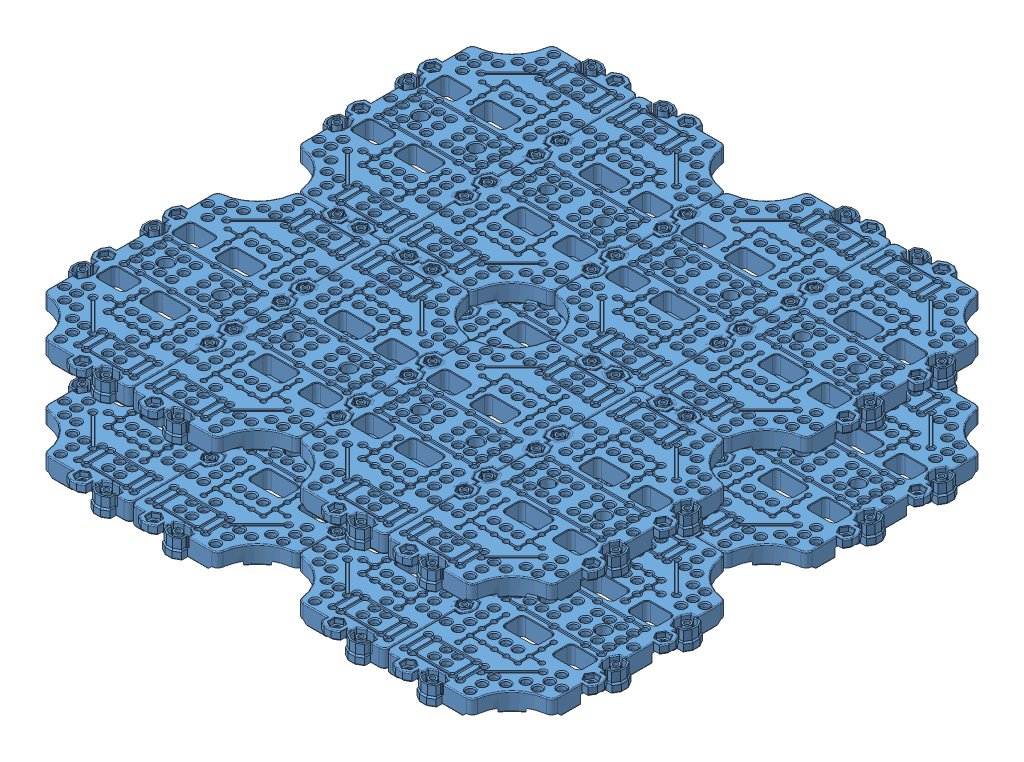
SolidWorks assembly layer, configuration 預設. Lengths in mm.
Overall size (348.29 59.85 366.75).
22 component instances, 1 part files, 0 mates.
Components (placement in the parent):
- 組合件4^layer-1: 組合件4^layer [預設] at origin size (348.29 9.85 366.75) (virtual)
  - 複製 of 組合件3^組合件4_layer-1: 複製 of 組合件3^組合件4_layer [預設] at (61.6154 0 -10.7198) size (265.55 9.85 137.55) (virtual)
    - waffle_plate - P-BP-A001_3D-1: waffle_plate - P-BP-A001_3D [Default] at (41.4794 2.9137 137.552) x (-1 0 0) z (0 0 -1) size (73.55 9.85 137.55)
    - waffle_plate - P-BP-A001_3D-2: waffle_plate - P-BP-A001_3D [Default] at (-86.5206 2.9137 137.552) size (73.55 9.85 137.55)
    - waffle_plate - P-BP-A001_3D-3: waffle_plate - P-BP-A001_3D [Default] at (-86.5206 2.9137 137.552) x (-1 0 0) z (0 0 -1) size (73.55 9.85 137.55)
    - waffle_plate - P-BP-A001_3D-4: waffle_plate - P-BP-A001_3D [Default] at (41.4794 2.9137 137.552) size (73.55 9.85 137.55)
  - 複製 of 組合件2^組合件4_layer-1: 複製 of 組合件2^組合件4_layer [預設] at (91.7846 0 -70.2364) x (0.907561 0 0.41992) z (-0.41992 0 0.907561) size (298.77 9.85 236.35) (virtual)
    - waffle_plate - P-BP-A001_3D-1: waffle_plate - P-BP-A001_3D [Default] at (146.7675 2.9137 290.2703) x (0.907561 0 -0.41992) z (0.41992 0 0.907561) size (73.55 9.85 137.55)
    - waffle_plate - P-BP-A001_3D-2: waffle_plate - P-BP-A001_3D [Default] at (30.5997 2.9137 344.02) x (-0.907561 0 0.41992) z (-0.41992 0 -0.907561) size (73.55 9.85 137.55)
    - waffle_plate - P-BP-A001_3D-3: waffle_plate - P-BP-A001_3D [Default] at (30.5997 2.9137 344.02) x (0.907561 0 -0.41992) z (0.41992 0 0.907561) size (73.55 9.85 137.55)
    - waffle_plate - P-BP-A001_3D-4: waffle_plate - P-BP-A001_3D [Default] at (146.7675 2.9137 290.2703) x (-0.907561 0 0.41992) z (-0.41992 0 -0.907561) size (73.55 9.85 137.55)
- 組合件4^layer-2: 組合件4^layer [預設] at (0 50 0) size (348.29 9.85 366.75) (virtual)
  - 複製 of 組合件3^組合件4_layer-1: 複製 of 組合件3^組合件4_layer [預設] at (61.6154 0 -10.7198) size (265.55 9.85 137.55) (virtual)
    - waffle_plate - P-BP-A001_3D-1: waffle_plate - P-BP-A001_3D [Default] at (41.4794 2.9137 137.552) x (-1 0 0) z (0 0 -1) size (73.55 9.85 137.55)
    - waffle_plate - P-BP-A001_3D-2: waffle_plate - P-BP-A001_3D [Default] at (-86.5206 2.9137 137.552) size (73.55 9.85 137.55)
    - waffle_plate - P-BP-A001_3D-3: waffle_plate - P-BP-A001_3D [Default] at (-86.5206 2.9137 137.552) x (-1 0 0) z (0 0 -1) size (73.55 9.85 137.55)
    - waffle_plate - P-BP-A001_3D-4: waffle_plate - P-BP-A001_3D [Default] at (41.4794 2.9137 137.552) size (73.55 9.85 137.55)
  - 複製 of 組合件2^組合件4_layer-1: 複製 of 組合件2^組合件4_layer [預設] at (91.7846 0 -70.2364) x (0.907561 0 0.41992) z (-0.41992 0 0.907561) size (298.77 9.85 236.35) (virtual)
    - waffle_plate - P-BP-A001_3D-1: waffle_plate - P-BP-A001_3D [Default] at (146.7675 2.9137 290.2703) x (0.907561 0 -0.41992) z (0.41992 0 0.907561) size (73.55 9.85 137.55)
    - waffle_plate - P-BP-A001_3D-2: waffle_plate - P-BP-A001_3D [Default] at (30.5997 2.9137 344.02) x (-0.907561 0 0.41992) z (-0.41992 0 -0.907561) size (73.55 9.85 137.55)
    - waffle_plate - P-BP-A001_3D-3: waffle_plate - P-BP-A001_3D [Default] at (30.5997 2.9137 344.02) x (0.907561 0 -0.41992) z (0.41992 0 0.907561) size (73.55 9.85 137.55)
    - waffle_plate - P-BP-A001_3D-4: waffle_plate - P-BP-A001_3D [Default] at (146.7675 2.9137 290.2703) x (-0.907561 0 0.41992) z (-0.41992 0 -0.907561) size (73.55 9.85 137.55)
